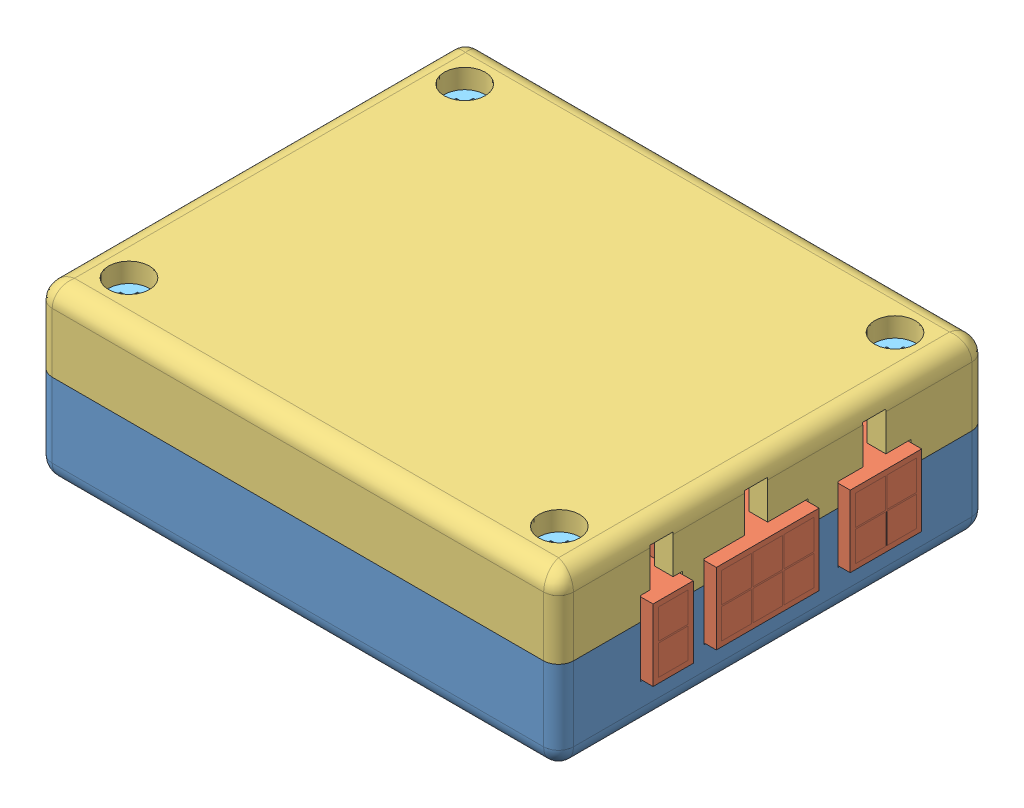
SolidWorks assembly Housing, configuration Standard. Lengths in mm.
Overall size (73.14 23 57.5).
11 component instances, 5 part files, 37 mates.
Components (placement in the parent):
- Housing-Bottom-1: Housing-Bottom [Standard] at (-70 0 57.5) size (70 12.5 57.5)
- Audio-Switch-1: Audio-Switch [Standard] at (-67.0675 4.8 54.4675) x (1 0 0) z (0 1 0) size (73.14 51.44 13.69)
- Housing-Top-1: Housing-Top [Standard] at (-70 20.5 57.5) size (70 15.9 57.5)
- hex thin nut chamfered gradeab_din-1: hex thin nut chamfered gradeab_din [Hexagon Thin Nut ISO 4035 - M3 - S] at (-63.8925 2 51.2925) x (1 0 0) z (0 1 0) size (5.5 6.35 1.8)
- hex thin nut chamfered gradeab_din-2: hex thin nut chamfered gradeab_din [Hexagon Thin Nut ISO 4035 - M3 - S] at (-63.8925 2 6.2075) x (1 0 0) z (0 1 0) size (5.5 6.35 1.8)
- hex thin nut chamfered gradeab_din-3: hex thin nut chamfered gradeab_din [Hexagon Thin Nut ISO 4035 - M3 - S] at (-6.1075 2 6.2075) x (1 0 0) z (0 1 0) size (5.5 6.35 1.8)
- hex thin nut chamfered gradeab_din-4: hex thin nut chamfered gradeab_din [Hexagon Thin Nut ISO 4035 - M3 - S] at (-6.1075 2 51.2925) x (1 0 0) z (0 1 0) size (5.5 6.35 1.8)
- countersunk flat head cross recess screw_din-1: countersunk flat head cross recess screw_din [DIN EN ISO 7046-1 - M3 x 20 - Z - 20S] at (-6.1075 20.4 6.2075) x (0 -1 0) z (0 0 1) size (20 5.5 5.5)
- countersunk flat head cross recess screw_din-2: countersunk flat head cross recess screw_din [DIN EN ISO 7046-1 - M3 x 20 - Z - 20S] at (-6.1075 20.4 51.2925) x (0 -1 0) z (0 0 1) size (20 5.5 5.5)
- countersunk flat head cross recess screw_din-3: countersunk flat head cross recess screw_din [DIN EN ISO 7046-1 - M3 x 20 - Z - 20S] at (-63.8925 20.4 6.2075) x (0 -1 0) z (0 0 1) size (20 5.5 5.5)
- countersunk flat head cross recess screw_din-4: countersunk flat head cross recess screw_din [DIN EN ISO 7046-1 - M3 x 20 - Z - 20S] at (-63.8925 20.4 51.2925) x (0 -1 0) z (0 0 1) size (20 5.5 5.5)
Mates (geometry in assembly coordinates):
- Deckungsgleich4: coincident anti-aligned: plane of Housing-Bottom-1 through (-63.8925 4 51.2925) normal (0 1 0); plane of Audio-Switch-1 through (-67.0675 4 54.4675) normal (0 -1 0)
- Deckungsgleich5: coincident anti-aligned: plane of Housing-Bottom-1 through (-68 12.5 2) normal (0 1 0); plane of Housing-Top-1 through (-70 12.5 57.5) normal (0 -1 0)
- Deckungsgleich6: coincident aligned: plane of Housing-Bottom-1 through (-70 2.5 55.5) normal (-1 0 0); plane of Housing-Top-1 through (-70 23 55.5) normal (-1 0 0)
- Deckungsgleich7: coincident aligned: plane of Housing-Bottom-1 through (-68 2.5 57.5) normal (0 0 1); plane of Housing-Top-1 through (-68 23 57.5) normal (0 0 1)
- Deckungsgleich8: coincident anti-aligned: plane of Housing-Top-1 through (-63.46 20 5.675) normal (0 1 0); plane of ? through (-60.71 20 5.675) normal (0 -1 0)
- Deckungsgleich9: coincident anti-aligned: plane of Housing-Top-1 through (-63.46 20 50.76) normal (0 1 0); plane of ? through (-60.71 20 50.76) normal (0 -1 0)
- Deckungsgleich10: coincident anti-aligned: plane of Housing-Top-1 through (-5.675 20 5.675) normal (0 1 0); plane of ? through (-2.925 20 5.675) normal (0 -1 0)
- Deckungsgleich11: coincident anti-aligned: plane of Housing-Top-1 through (-5.675 20 50.76) normal (0 1 0); plane of ? through (-2.925 20 50.76) normal (0 -1 0)
- Konzentrisch1: concentric anti-aligned: cylinder of Housing-Top-1 through (-63.46 23 5.675) axis (0 -1 0) radius 1.5; cylinder of ? through (-63.46 54.75 5.675) axis (0 1 0) radius 1.5
- Konzentrisch2: concentric anti-aligned: cylinder of Housing-Top-1 through (-63.46 23 50.76) axis (0 -1 0) radius 1.5; cylinder of ? through (-63.46 54.75 50.76) axis (0 1 0) radius 1.5
- Konzentrisch3: concentric anti-aligned: cylinder of Housing-Top-1 through (-5.675 23 5.675) axis (0 -1 0) radius 1.5; cylinder of ? through (-5.675 54.75 5.675) axis (0 1 0) radius 1.5
- Konzentrisch4: concentric anti-aligned: cylinder of Housing-Top-1 through (-5.675 23 50.76) axis (0 -1 0) radius 1.5; cylinder of ? through (-5.675 54.75 50.76) axis (0 1 0) radius 1.5
- Deckungsgleich12: coincident anti-aligned: plane of Housing-Bottom-1 through (-70 2 57.5) normal (0 -1 0); plane of hex thin nut chamfered gradeab_din-4 through (-6.1075 2 48.1171) normal (0 1 0)
- Deckungsgleich13: coincident anti-aligned: plane of Housing-Bottom-1 through (-70 2 57.5) normal (0 -1 0); plane of hex thin nut chamfered gradeab_din-3 through (-6.1075 2 3.0321) normal (0 1 0)
- Deckungsgleich15: coincident anti-aligned: plane of Housing-Bottom-1 through (-70 2 57.5) normal (0 -1 0); plane of hex thin nut chamfered gradeab_din-1 through (-63.8925 2 48.1171) normal (0 1 0)
- Deckungsgleich16: coincident anti-aligned: plane of Housing-Bottom-1 through (-70 2 57.5) normal (0 -1 0); plane of hex thin nut chamfered gradeab_din-2 through (-63.8925 2 3.0321) normal (0 1 0)
- Deckungsgleich17: coincident anti-aligned: plane of Housing-Bottom-1 through (-3.3575 2 49.7048) normal (-1 0 0); plane of hex thin nut chamfered gradeab_din-4 through (-3.3575 0.2 49.7048) normal (1 0 0)
- Deckungsgleich18: coincident anti-aligned: plane of Housing-Bottom-1 through (-3.3575 2 52.8802) normal (-0.5 0 -0.866025); plane of hex thin nut chamfered gradeab_din-4 through (-6.1075 0.2 54.4679) normal (0.5 0 0.866025)
- Deckungsgleich19: coincident anti-aligned: plane of Housing-Bottom-1 through (-6.1075 2 3.0321) normal (-0.5 0 0.866025); plane of hex thin nut chamfered gradeab_din-3 through (-3.3575 0.2 4.6198) normal (0.5 0 -0.866025)
- Deckungsgleich20: coincident anti-aligned: plane of Housing-Bottom-1 through (-8.8575 2 4.6198) normal (0.5 0 0.866025); plane of hex thin nut chamfered gradeab_din-3 through (-6.1075 0.2 3.0321) normal (-0.5 0 -0.866025)
- Deckungsgleich21: coincident anti-aligned: plane of Housing-Bottom-1 through (-63.8925 2 48.1171) normal (-0.5 0 0.866025); plane of hex thin nut chamfered gradeab_din-1 through (-61.1425 0.2 49.7048) normal (0.5 0 -0.866025)
- Deckungsgleich22: coincident anti-aligned: plane of Housing-Bottom-1 through (-61.1425 2 49.7048) normal (-1 0 0); plane of hex thin nut chamfered gradeab_din-1 through (-61.1425 0.2 49.7048) normal (1 0 0)
- Deckungsgleich23: coincident anti-aligned: plane of Housing-Bottom-1 through (-61.1425 2 7.7952) normal (-0.5 0 -0.866025); plane of hex thin nut chamfered gradeab_din-2 through (-63.8925 0.2 9.3829) normal (0.5 0 0.866025)
- Deckungsgleich24: coincident anti-aligned: plane of Housing-Bottom-1 through (-61.1425 2 4.6198) normal (-1 0 0); plane of hex thin nut chamfered gradeab_din-2 through (-61.1425 0.2 4.6198) normal (1 0 0)
- Deckungsgleich25: coincident anti-aligned: plane of Housing-Bottom-1 through (-2 0 55.5) normal (0 -1 0); plane of assembly through (0 0 0) normal (0 1 0)
- Deckungsgleich26: coincident anti-aligned: plane of Housing-Bottom-1 through (-68 2.5 0) normal (0 0 -1); plane of assembly through (0 0 0) normal (0 0 1)
- Deckungsgleich27: coincident aligned: plane of Housing-Bottom-1 through (0 2.5 55.5) normal (1 0 0); plane of assembly through (0 0 0) normal (1 0 0)
- Deckungsgleich28: coincident aligned: cone of Housing-Top-1 through (-63.8925 18.75 51.2925) axis (0 -1 0); cone of countersunk flat head cross recess screw_din-4 through (-63.8925 20 51.2925) axis (0 -1 0)
- Deckungsgleich29: coincident aligned: cone of Housing-Top-1 through (-63.8925 18.75 6.2075) axis (0 -1 0); cone of countersunk flat head cross recess screw_din-3 through (-63.8925 20 6.2075) axis (0 -1 0)
- Deckungsgleich30: coincident aligned: cone of Housing-Top-1 through (-6.1075 18.75 6.2075) axis (0 -1 0); cone of countersunk flat head cross recess screw_din-1 through (-6.1075 20 6.2075) axis (0 -1 0)
- Deckungsgleich31: coincident aligned: cone of Housing-Top-1 through (-6.1075 18.75 51.2925) axis (0 -1 0); cone of countersunk flat head cross recess screw_din-2 through (-6.1075 20 51.2925) axis (0 -1 0)
- Parallel1: parallel: line of Housing-Top-1 through (-67.5 23 55) axis (1 0 0); plane of countersunk flat head cross recess screw_din-2 through (-6.6054 18.39 51.6625) normal (0 0 -1)
- Parallel2: parallel: line of Housing-Top-1 through (-67.5 23 55) axis (1 0 0); plane of countersunk flat head cross recess screw_din-4 through (-64.3904 18.39 51.6625) normal (0 0 -1)
- Parallel4: parallel: line of Housing-Top-1 through (-2.5 23 2.5) axis (-1 0 0); plane of countersunk flat head cross recess screw_din-3 through (-63.3946 18.39 5.8375) normal (0 0 1)
- Parallel5: parallel: line of Housing-Top-1 through (-2.5 23 2.5) axis (-1 0 0); plane of countersunk flat head cross recess screw_din-1 through (-5.6096 18.39 5.8375) normal (0 0 1)
- Konzentrisch5: concentric aligned: cylinder of Housing-Bottom-1 through (-63.8925 2.5 51.2925) axis (0 -1 0) radius 1.5; cylinder of Audio-Switch-1 through (-63.8925 4 51.2925) axis (0 -1 0) radius 1.55
- Konzentrisch6: concentric aligned: cylinder of Housing-Bottom-1 through (-6.1075 2.5 6.2075) axis (0 -1 0) radius 1.5; cylinder of Audio-Switch-1 through (-6.1075 4 6.2075) axis (0 -1 0) radius 1.55
